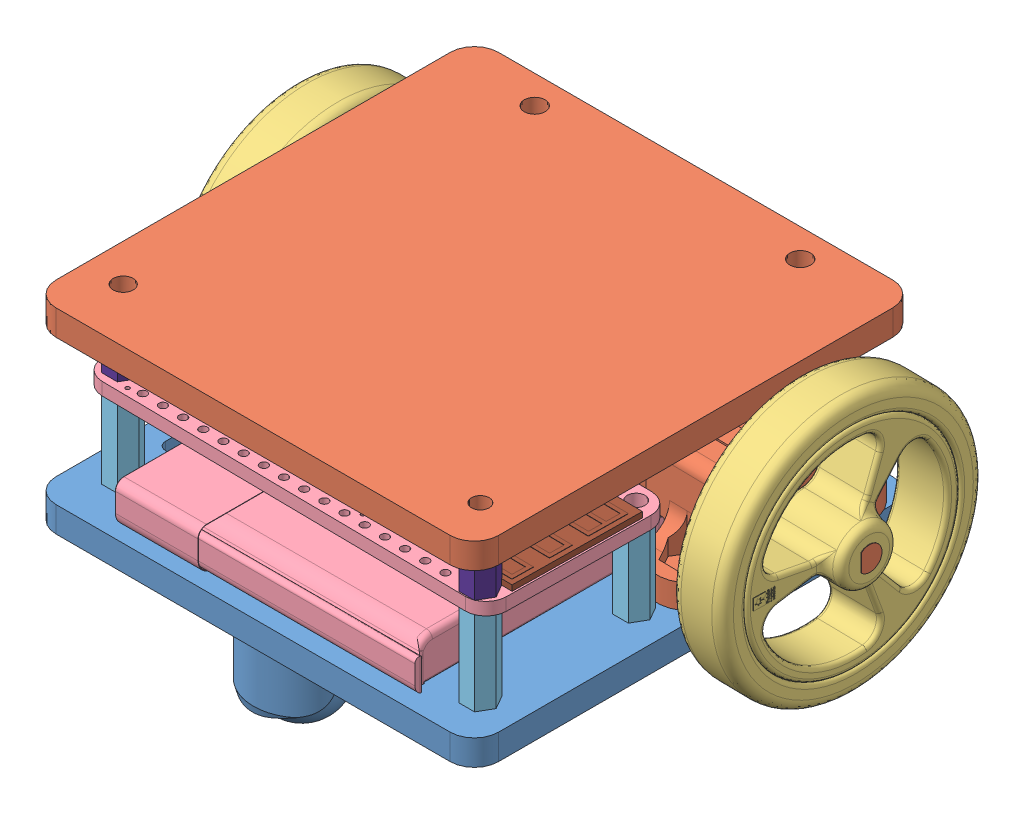
SolidWorks assembly Full Model, configuration Default. Lengths in mm.
Overall size (73.86 34.42 56.11).
54 component instances, 23 part files, 50 mates.
Components (placement in the parent):
- Base Plate-1: Base Plate [Default] at (27.9172 29.2724 44.5271) size (55 3.17 55)
- micro-metal-gearmotor-with-1086-bracket-3: micro-metal-gearmotor-with-1086-bracket [Default] at (9.5456 37.4473 32.0706) x (-0.999962 0 -0.008727) z (0.008727 0 -0.999962) size (35.27 11.71 26.51)
- micro-metal-gearmotor-with-1086-bracket-4: micro-metal-gearmotor-with-1086-bracket [Default] at (46.525 37.4473 31.942) x (0.999848 0 0.017452) z (-0.017452 0 0.999848) size (35.27 11.71 26.51)
- pololu-wheel-32x7mm-black-1: pololu-wheel-32x7mm-black [Default] at (-3.354 37.4473 31.958) x (0 -1 0) z (0.999962 0 0.008727) size (32 32 8.6)
- pololu-wheel-32x7mm-black-2: pololu-wheel-32x7mm-black [Default] at (59.4231 37.4473 32.1672) x (0 -1 0) z (-0.999848 0 -0.017452) size (32 32 8.6)
- 2821 Adafruit ESP8266 Feather-1: 2821 Adafruit ESP8266 Feather [Default] at (2.4928 42.8774 67.8684) x (0.99992 0 0.012651) z (0 1 0) size (51.25 22.86 6.37)
  - 2821 Adafruit ESP8266 Feather.step-1: 2821 Adafruit ESP8266 Feather.step [Default] at origin size (51.25 22.86 6.37)
    - PCB Component.step-1: PCB Component.step [Default] at origin size (51.25 22.86 6.37)
      - Board.step-1: Board.step [Default] at origin size (50.8 22.86 1.57)
      - 10uF.step-1: 10uF.step [Default] at (8.088 12.959 1.57) x (0 1 0) z (0 0 1) size (2 1.25 1)
      - 10uF.step-2: 10uF.step [Default] at (14.366 12.64 1.57) x (0 -1 0) z (0 0 1) size (2 1.25 1)
      - 10uF.step-3: 10uF.step [Default] at (11.049 12.192 1.57) x (-1 0 0) z (0 0 1) size (2 1.25 1)
      - 10uF.step-4: 10uF.step [Default] at (21.463 16.192 1.57) x (0 -1 0) z (0 0 1) size (2 1.25 1)
      - 10K.step-1: 10K.step [Default] at (12.302 4.775 1.57) x (0 -1 0) z (0 0 1) size (1.62 0.81 0.38)
      - 10K.step-2: 10K.step [Default] at (6.223 4.191 1.57) size (1.62 0.81 0.38)
      - 10K.step-3: 10K.step [Default] at (20.828 12.7 1.57) x (0 -1 0) z (0 0 1) size (1.62 0.81 0.38)
      - 10K.step-4: 10K.step [Default] at (24.257 18.923 1.57) x (-1 0 0) z (0 0 1) size (1.62 0.81 0.38)
      - 10K.step-5: 10K.step [Default] at (24.257 17.526 1.57) x (-1 0 0) z (0 0 1) size (1.62 0.81 0.38)
      - 10K.step-6: 10K.step [Default] at (24.384 3.937 1.57) size (1.62 0.81 0.38)
      - 10K.step-7: 10K.step [Default] at (24.384 5.334 1.57) x (-1 0 0) z (0 0 1) size (1.62 0.81 0.38)
      - 10K.step-8: 10K.step [Default] at (5.588 21.082 1.57) x (0 -1 0) z (0 0 1) size (1.62 0.81 0.38)
      - 10K.step-9: 10K.step [Default] at (24.003 11.938 1.57) x (-1 0 0) z (0 0 1) size (1.62 0.81 0.38)
      - 10K.step-10: 10K.step [Default] at (17.78 17.272 1.57) size (1.62 0.81 0.38)
      - MCP73831T-2ACI_OT.step-1: MCP73831T-2ACI_OT.step [Default] at (17.78 14.986 1.57) x (0 1 0) z (0 0 1) size (3 3 1.4)
      - MCP73831T-2ACI_OT.step-2: MCP73831T-2ACI_OT.step [Default] at (17.78 11.557 1.57) x (0 -1 0) z (0 0 1) size (3 3 1.4)
      - MBR120.step-1: MBR120.step [Default] at (17.907 18.796 1.57) x (-1 0 0) z (0 0 1) size (3.6 1.4 1.35)
      - JSTPH.step-1: JSTPH.step [Default] at (10.795 19.304 1.57) size (7.9 8.6 4.8)
      - RED.step-1: RED.step [Default] at (2.413 5.588 1.57) x (0 -1 0) z (0 0 1) size (1.25 2.02 1.1)
      - RED.step-2: RED.step [Default] at (2.858 17.336 1.57) x (0 -1 0) z (0 0 1) size (1.25 2.02 1.1)
      - ESP-12.step-1: ESP-12.step [Default] at (36.322 11.43 1.57) x (0 -1 0) z (0 0 1) size (16 24 2.95)
      - KMR2.step-1: KMR2.step [Default] at (9.398 6.35 1.57) x (0 -1 0) z (0 0 1) size (4.6 2.8 1.94)
      - CP2104.step-1: CP2104.step [Default] at (16.256 6.477 1.57) size (4 4 1)
      - 20329.step-1: 20329.step [Default] at (4.445 11.43 1.57) x (0 -1 0) z (0 0 1) size (8.8 5.6 3)
      - 1K.step-1: 1K.step [Default] at (24.003 10.541 1.57) size (1.6 0.9 0.8)
      - 1K.step-2: 1K.step [Default] at (19.812 8.382 1.57) x (0 -1 0) z (0 0 1) size (1.6 0.9 0.8)
      - mmbt2222.step-1: mmbt2222.step [Default] at (24.003 8.001 1.57) x (-1 0 0) z (0 0 1) size (3.04 2.64 1.12)
      - mmbt2222.step-2: mmbt2222.step [Default] at (24.003 14.986 1.57) size (3.04 2.64 1.12)
- 6mm Standoff-5: 6mm Standoff [Default] at (17.7572 38.4474 21.2871) size (3.92 6 3.39)
- 6mm Standoff-6: 6mm Standoff [Default] at (38.0772 38.4474 21.2871) size (3.92 6 3.39)
- 6mm Standoff-7: 6mm Standoff [Default] at (17.7572 32.4474 21.2871) size (3.92 6 3.39)
- 6mm Standoff-8: 6mm Standoff [Default] at (38.0772 32.4474 21.2871) size (3.92 6 3.39)
- Adafruit DRV8833 Motor Driver-1: Adafruit DRV8833 Motor Driver [Default] at (27.9172 44.4474 27.6371) x (0 0 -1) z (1 0 0) size (17.78 2 25.4)
- pololu-ball-caster-with-0-375in-ball-1: pololu-ball-caster-with-0-375in-ball [Default] at (27.9362 27.7484 65.9771) x (1 0 0) z (0 -1 0) size (19.05 12.07 10.07)
- Top Plate-1: Top Plate [Default] at (27.9172 50.4474 44.5271) size (55 3.17 55)
- Tall Standoff-1: Tall Standoff [Default] at (44.4172 32.4474 20.5271) size (3.92 18 3.39)
- Tall Standoff-2: Tall Standoff [Default] at (11.4172 32.4474 20.5271) size (3.92 18 3.39)
- 6mm Standoff-9: 6mm Standoff [Default] at (50.7722 44.4474 66.6371) size (3.92 6 3.39)
- 6mm Standoff-10: 6mm Standoff [Default] at (5.0522 44.4474 65.3071) x (0.99998 0 0.006381) z (-0.006381 0 0.99998) size (3.92 6 3.39)
- Li Bat 503035P-2: Li Bat 503035P [Default] at (10.0672 35.0324 55.4771) x (0 0 -1) z (1 0 0) size (31.21 5.82 37.21)
- 10mm Standoff-3: 10mm Standoff [Default] at (5.0522 32.4474 65.3071) size (3.92 10.43 3.39)
- 10mm Standoff-4: 10mm Standoff [Default] at (50.7722 32.4474 66.6371) size (3.92 10.43 3.39)
- 10mm Standoff-5: 10mm Standoff [Default] at (50.7722 32.4474 47.5271) size (3.92 10.43 3.39)
- 10mm Standoff-6: 10mm Standoff [Default] at (5.0522 32.4474 47.5271) size (3.92 10.43 3.39)
- Li Bat 503035P-3: Li Bat 503035P [Default] at (10.0672 26.6874 41.4771) x (0 0 1) z (1 0 0) size (31.21 5.82 37.21)
Mates (geometry in assembly coordinates):
- Coincident7: coincident anti-aligned: plane of Base Plate-1 through (27.9172 32.4474 44.5271) normal (0 1 0); plane of micro-metal-gearmotor-with-1086-bracket-3 through (9.5456 32.4474 32.0706) normal (0 -1 0)
- Concentric8: concentric aligned: cylinder of Base Plate-1 through (4.5172 25.5954 41.0271) axis (0 1 0) radius 1.3; cylinder of micro-metal-gearmotor-with-1086-bracket-3 through (4.5172 32.4473 41.0271) axis (0 1 0) radius 1.15
- Coincident8: coincident anti-aligned: plane of Base Plate-1 through (27.9172 32.4474 44.5271) normal (0 1 0); plane of micro-metal-gearmotor-with-1086-bracket-4 through (46.525 32.4474 31.942) normal (0 -1 0)
- Concentric9: concentric aligned: cylinder of Base Plate-1 through (51.3172 25.5954 41.0271) axis (0 1 0) radius 1.3; cylinder of micro-metal-gearmotor-with-1086-bracket-4 through (51.3172 32.4473 41.0271) axis (0 1 0) radius 1.15
- Coincident9: coincident anti-aligned: plane of micro-metal-gearmotor-with-1086-bracket-3 through (-9.445 38.5653 30.9048) normal (0.008727 0 -0.999962); plane of pololu-wheel-32x7mm-black-1 through (-8.645 36.3293 30.9118) normal (-0.008727 0 0.999962)
- Coincident10: coincident anti-aligned: plane of micro-metal-gearmotor-with-1086-bracket-3 through (-0.0541 37.4473 31.9868) normal (-0.999962 0 -0.008727); plane of pololu-wheel-32x7mm-black-1 through (-0.0541 37.4473 31.9868) normal (0.999962 0 0.008727)
- Concentric10: concentric aligned: cylinder of micro-metal-gearmotor-with-1086-bracket-3 through (-9.4537 37.4473 31.9048) axis (0.999962 0 0.008727) radius 1.5; cylinder of pololu-wheel-32x7mm-black-1 through (-8.6538 37.4473 31.9118) axis (0.999962 0 0.008727) radius 1.5
- Concentric11: concentric aligned: cylinder of micro-metal-gearmotor-with-1086-bracket-4 through (65.5221 37.4473 32.2736) axis (-0.999848 0 -0.017452) radius 1.5; cylinder of pololu-wheel-32x7mm-black-2 through (64.7223 37.4473 32.2597) axis (-0.999848 0 -0.017452) radius 1.5
- Coincident11: coincident anti-aligned: plane of micro-metal-gearmotor-with-1086-bracket-4 through (56.1236 37.4473 32.1096) normal (0.999848 0 0.017452); plane of pololu-wheel-32x7mm-black-2 through (56.1236 37.4473 32.1096) normal (-0.999848 0 -0.017452)
- Coincident12: coincident anti-aligned: plane of micro-metal-gearmotor-with-1086-bracket-4 through (65.5047 38.5653 33.2735) normal (-0.017452 0 0.999848); plane of pololu-wheel-32x7mm-black-2 through (64.7048 36.3293 33.2595) normal (0.017452 0 -0.999848)
- Concentric32: concentric anti-aligned: cylinder of Base Plate-1 through (17.7572 26.0197 21.2871) axis (0 1 0) radius 1.15; cylinder of 6mm Standoff-7 through (17.7572 38.4474 21.2871) axis (0 -1 0) radius 1.3
- Concentric33: concentric anti-aligned: cylinder of Base Plate-1 through (38.0772 26.0197 21.2871) axis (0 1 0) radius 1.15; cylinder of 6mm Standoff-8 through (38.0772 38.4474 21.2871) axis (0 -1 0) radius 1.3
- Coincident21: coincident anti-aligned: plane of Base Plate-1 through (27.9172 32.4474 44.5271) normal (0 1 0); plane of 6mm Standoff-7 through (17.7572 32.4474 21.2871) normal (0 -1 0)
- Coincident22: coincident anti-aligned: plane of Base Plate-1 through (27.9172 32.4474 44.5271) normal (0 1 0); plane of 6mm Standoff-8 through (38.0772 32.4474 21.2871) normal (0 -1 0)
- Coincident23: coincident anti-aligned: plane of 6mm Standoff-5 through (17.7572 38.4474 21.2871) normal (0 -1 0); plane of 6mm Standoff-7 through (17.7572 38.4474 21.2871) normal (0 1 0)
- Concentric34: concentric aligned: cylinder of 6mm Standoff-5 through (17.7572 44.4474 21.2871) axis (0 -1 0) radius 1.3; cylinder of 6mm Standoff-7 through (17.7572 38.4474 21.2871) axis (0 -1 0) radius 1.3
- Coincident24: coincident anti-aligned: plane of 6mm Standoff-6 through (38.0772 38.4474 21.2871) normal (0 -1 0); plane of 6mm Standoff-8 through (38.0772 38.4474 21.2871) normal (0 1 0)
- Concentric35: concentric aligned: cylinder of 6mm Standoff-6 through (38.0772 44.4474 21.2871) axis (0 -1 0) radius 1.3; cylinder of 6mm Standoff-8 through (38.0772 38.4474 21.2871) axis (0 -1 0) radius 1.3
- Concentric36: concentric anti-aligned: cylinder of 6mm Standoff-5 through (17.7572 44.4474 21.2871) axis (0 -1 0) radius 1.3; cylinder of Adafruit DRV8833 Motor Driver-1 through (17.7572 41.1947 21.2871) axis (0 1 0) radius 1.15
- Coincident25: coincident anti-aligned: plane of 6mm Standoff-5 through (17.7572 44.4474 21.2871) normal (0 1 0); plane of Adafruit DRV8833 Motor Driver-1 through (27.9172 44.4474 27.6371) normal (0 -1 0)
- Concentric37: concentric anti-aligned: cylinder of 6mm Standoff-6 through (38.0772 44.4474 21.2871) axis (0 -1 0) radius 1.3; cylinder of Adafruit DRV8833 Motor Driver-1 through (38.0772 41.1947 21.2871) axis (0 1 0) radius 1.15
- Coincident26: coincident anti-aligned: plane of Base Plate-1 through (27.9172 29.2724 44.5271) normal (0 -1 0); plane of pololu-ball-caster-with-0-375in-ball-1 through (18.3079 29.2724 59.9446) normal (0 1 0)
- Concentric38: concentric anti-aligned: cylinder of Base Plate-1 through (34.6672 26.0197 65.9771) axis (0 1 0) radius 1.15; cylinder of pololu-ball-caster-with-0-375in-ball-1 through (34.6672 27.7484 65.9771) axis (0 -1 0) radius 1.143
- Concentric39: concentric anti-aligned: cylinder of Base Plate-1 through (11.4172 25.5954 20.5271) axis (0 1 0) radius 1.3; cylinder of Tall Standoff-2 through (11.4172 50.4474 20.5271) axis (0 -1 0) radius 1.3
- Concentric40: concentric anti-aligned: cylinder of Base Plate-1 through (44.4172 25.5954 20.5271) axis (0 1 0) radius 1.3; cylinder of Tall Standoff-1 through (44.4172 50.4474 20.5271) axis (0 -1 0) radius 1.3
- Coincident27: coincident anti-aligned: plane of Base Plate-1 through (27.9172 32.4474 44.5271) normal (0 1 0); plane of Tall Standoff-2 through (11.4172 32.4474 20.5271) normal (0 -1 0)
- Coincident28: coincident anti-aligned: plane of Base Plate-1 through (27.9172 32.4474 44.5271) normal (0 1 0); plane of Tall Standoff-1 through (44.4172 32.4474 20.5271) normal (0 -1 0)
- Coincident29: coincident anti-aligned: plane of Top Plate-1 through (27.9172 50.4474 44.5271) normal (0 -1 0); plane of Tall Standoff-2 through (11.4172 50.4474 20.5271) normal (0 1 0)
- Concentric41: concentric anti-aligned: cylinder of Top Plate-1 through (44.4172 46.7704 20.5271) axis (0 1 0) radius 1.3; cylinder of Tall Standoff-1 through (44.4172 50.4474 20.5271) axis (0 -1 0) radius 1.3
- Concentric42: concentric anti-aligned: cylinder of Top Plate-1 through (11.4172 46.7704 20.5271) axis (0 1 0) radius 1.3; cylinder of Tall Standoff-2 through (11.4172 50.4474 20.5271) axis (0 -1 0) radius 1.3
- Concentric45: concentric anti-aligned: cylinder of Top Plate-1 through (5.0522 46.9119 65.3071) axis (0 1 0) radius 1.25; cylinder of 6mm Standoff-10 through (5.0522 50.4474 65.3071) axis (0 -1 0) radius 1.3
- Concentric46: concentric anti-aligned: cylinder of Top Plate-1 through (50.7722 46.9119 66.6371) axis (0 1 0) radius 1.1; cylinder of 6mm Standoff-9 through (50.7722 50.4474 66.6371) axis (0 -1 0) radius 1.3
- Coincident32: coincident anti-aligned: plane of Top Plate-1 through (27.9172 50.4474 44.5271) normal (0 -1 0); plane of 6mm Standoff-9 through (50.7722 50.4474 66.6371) normal (0 1 0)
- Coincident33: coincident anti-aligned: plane of Top Plate-1 through (27.9172 50.4474 44.5271) normal (0 -1 0); plane of 6mm Standoff-10 through (5.0522 50.4474 65.3071) normal (0 1 0)
- Concentric47: concentric anti-aligned: cylinder of 2821 Adafruit ESP8266 Feather-1/2821 Adafruit ESP8266 Feather.step-1/PCB Component.step-1/Board.step-1 through (50.7722 42.8774 66.6371) axis (0 1 0) radius 1.1; cylinder of 6mm Standoff-9 through (50.7722 50.4474 66.6371) axis (0 -1 0) radius 1.3
- Coincident34: coincident anti-aligned: plane of 2821 Adafruit ESP8266 Feather-1/2821 Adafruit ESP8266 Feather.step-1/PCB Component.step-1/Board.step-1 through (28.0353 44.4474 56.7606) normal (0 1 0); plane of 6mm Standoff-9 through (50.7722 44.4474 66.6371) normal (0 -1 0)
- Coincident36: coincident anti-aligned: plane of Base Plate-1 through (27.9172 32.4474 44.5271) normal (0 1 0); plane of Li Bat 503035P-2 through (10.0672 32.4474 69.2771) normal (0 -1 0)
- Distance1: distance = 1 mm aligned: plane of Li Bat 503035P-2 through (10.0672 36.5674 71.0271) normal (0 0 1); plane of Base Plate-1 through (0.4172 32.4474 72.0271) normal (0 0 1)
- Distance2: distance = 9.35 mm aligned: plane of Li Bat 503035P-2 through (9.7672 35.0324 57.2384) normal (-1 0 0); plane of Base Plate-1 through (0.4172 32.4474 17.0271) normal (-1 0 0)
- Concentric48: concentric anti-aligned: cylinder of Base Plate-1 through (5.0522 25.7369 65.3071) axis (0 1 0) radius 1.25; cylinder of 10mm Standoff-3 through (5.0522 42.8774 65.3071) axis (0 -1 0) radius 1.3
- Concentric49: concentric anti-aligned: cylinder of Base Plate-1 through (50.7722 25.7369 66.6371) axis (0 1 0) radius 1.1; cylinder of 10mm Standoff-4 through (50.7722 42.8774 66.6371) axis (0 -1 0) radius 1.3
- Coincident39: coincident anti-aligned: plane of Base Plate-1 through (27.9172 32.4474 44.5271) normal (0 1 0); plane of 10mm Standoff-3 through (5.0522 32.4474 65.3071) normal (0 -1 0)
- Coincident40: coincident anti-aligned: plane of Base Plate-1 through (27.9172 32.4474 44.5271) normal (0 1 0); plane of 10mm Standoff-4 through (50.7722 32.4474 66.6371) normal (0 -1 0)
- Concentric50: concentric anti-aligned: cylinder of Base Plate-1 through (5.0522 25.7369 47.5271) axis (0 1 0) radius 1.25; cylinder of 10mm Standoff-6 through (5.0522 42.8774 47.5271) axis (0 -1 0) radius 1.3
- Concentric51: concentric anti-aligned: cylinder of Base Plate-1 through (50.7722 25.7369 47.5271) axis (0 1 0) radius 1.1; cylinder of 10mm Standoff-5 through (50.7722 42.8774 47.5271) axis (0 -1 0) radius 1.3
- Coincident41: coincident anti-aligned: plane of Base Plate-1 through (27.9172 32.4474 44.5271) normal (0 1 0); plane of 10mm Standoff-6 through (5.0522 32.4474 47.5271) normal (0 -1 0)
- Coincident42: coincident anti-aligned: plane of Base Plate-1 through (27.9172 32.4474 44.5271) normal (0 1 0); plane of 10mm Standoff-5 through (50.7722 32.4474 47.5271) normal (0 -1 0)
- Coincident43: coincident anti-aligned: plane of Base Plate-1 through (27.9172 29.2724 44.5271) normal (0 -1 0); plane of Li Bat 503035P-3 through (10.0672 29.2724 27.6771) normal (0 1 0)
- Distance3: distance = 9.35 mm aligned: plane of Li Bat 503035P-3 through (9.7672 26.6874 39.7158) normal (-1 0 0); plane of Base Plate-1 through (0.4172 32.4474 17.0271) normal (-1 0 0)
- Distance4: distance = 15 mm aligned: plane of Li Bat 503035P-3 through (10.0672 27.5224 57.0271) normal (0 0 1); plane of Base Plate-1 through (0.4172 32.4474 72.0271) normal (0 0 1)
